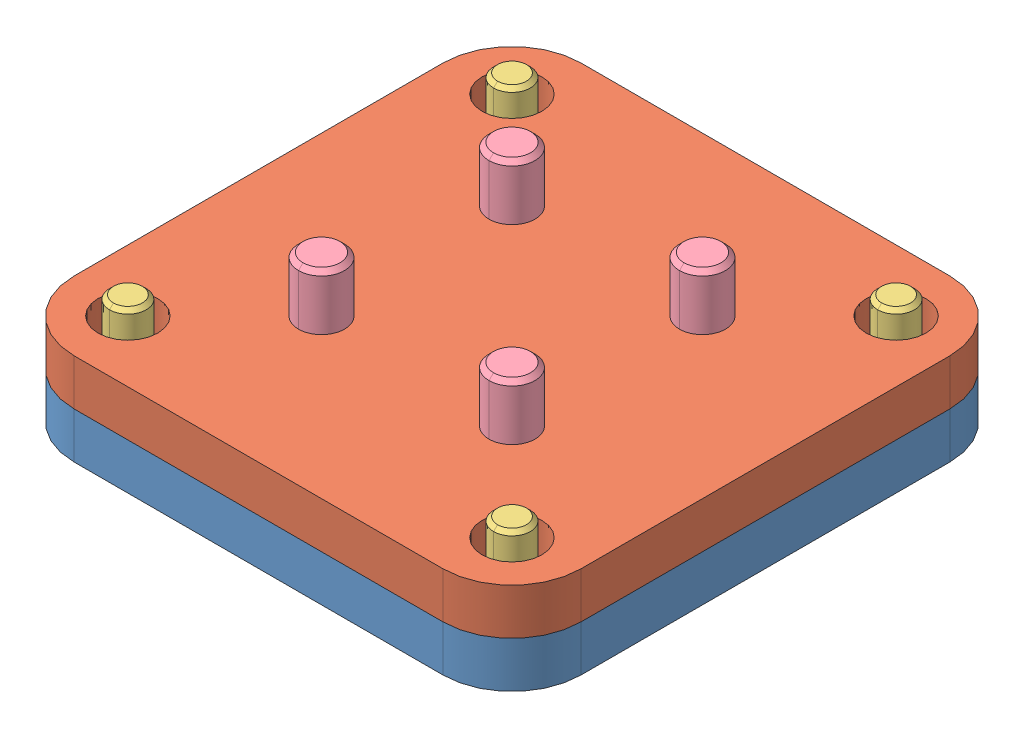
SolidWorks assembly Wheel Adapter V4, configuration Default. Lengths in mm.
Overall size (55.1 18.21 55.1).
10 component instances, 4 part files, 19 mates.
Components (placement in the parent):
- Base plate-1: Base plate [Default] at (35.6102 25.5651 34.2597) size (55.1 5 55.1)
- Connector plate-1: Connector plate [Default] at (35.6102 30.5651 34.2597) size (55.1 5 55.1)
- Screw_ISO_7380_1_M4x12_07151_040_012_High_-2: Screw_ISO_7380_1_M4x12_07151_040_012_High_ [Default] at (14.7402 25.5651 55.1297) x (0 1 0) z (0 0 1) size (14.21 7.6 7.6)
- Screw_ISO_7380_1_M4x12_07151_040_012_High_-3: Screw_ISO_7380_1_M4x12_07151_040_012_High_ [Default] at (14.7402 25.5651 13.3897) x (0 1 0) z (0 0 1) size (14.21 7.6 7.6)
- Screw_ISO_7380_1_M4x12_07151_040_012_High_-4: Screw_ISO_7380_1_M4x12_07151_040_012_High_ [Default] at (56.4802 25.5651 13.3897) x (0 1 0) z (0 0 1) size (14.21 7.6 7.6)
- Screw_ISO_7380_1_M4x12_07151_040_012_High_-5: Screw_ISO_7380_1_M4x12_07151_040_012_High_ [Default] at (56.4802 25.5651 55.1297) x (0 1 0) z (0 0 1) size (14.21 7.6 7.6)
- Screw_ISO_7380_1_M5x8_07150_050_008_High_-1: Screw_ISO_7380_1_M5x8_07150_050_008_High_ [Default] at (45.9602 33.5651 44.6097) x (0 1 0) z (0 0 1) size (10.76 9.5 9.5)
- Screw_ISO_7380_1_M5x8_07150_050_008_High_-2: Screw_ISO_7380_1_M5x8_07150_050_008_High_ [Default] at (45.9602 33.5651 23.9097) x (0 1 0) z (0 0 1) size (10.76 9.5 9.5)
- Screw_ISO_7380_1_M5x8_07150_050_008_High_-3: Screw_ISO_7380_1_M5x8_07150_050_008_High_ [Default] at (25.2602 33.5651 23.9097) x (0 1 0) z (0 0 1) size (10.76 9.5 9.5)
- Screw_ISO_7380_1_M5x8_07150_050_008_High_-4: Screw_ISO_7380_1_M5x8_07150_050_008_High_ [Default] at (25.2602 33.5651 44.6097) x (0 1 0) z (0 0 1) size (10.76 9.5 9.5)
Mates (geometry in assembly coordinates):
- Coincident2: coincident aligned: plane of Base plate-1 through (63.1602 30.5651 61.8097) normal (1 0 0); plane of Connector plate-1 through (63.1602 70.2532 61.8097) normal (1 0 0)
- Coincident3: coincident aligned: plane of Base plate-1 through (8.0602 30.5651 61.8097) normal (0 0 1); plane of Connector plate-1 through (8.0602 70.2532 61.8097) normal (0 0 1)
- Coincident4: coincident anti-aligned: plane of Base plate-1 through (35.6102 25.5651 34.2597) normal (0 -1 0); plane of Screw_ISO_7380_1_M4x12_07151_040_012_High_-2 through (14.7402 25.5651 57.1297) normal (0 1 0)
- Coincident5: coincident aligned: line of Base plate-1 through (14.7402 30.5651 55.1297) axis (0 -1 0); line of Screw_ISO_7380_1_M4x12_07151_040_012_High_-2 through (14.7402 37.1356 55.1297) axis (0 -1 0)
- Coincident6: coincident anti-aligned: plane of Base plate-1 through (35.6102 25.5651 34.2597) normal (0 -1 0); plane of Screw_ISO_7380_1_M4x12_07151_040_012_High_-5 through (56.4802 25.5651 57.1297) normal (0 1 0)
- Coincident7: coincident aligned: line of Base plate-1 through (56.4802 30.5651 55.1297) axis (0 -1 0); line of Screw_ISO_7380_1_M4x12_07151_040_012_High_-5 through (56.4802 37.1356 55.1297) axis (0 -1 0)
- Coincident8: coincident anti-aligned: plane of Base plate-1 through (35.6102 25.5651 34.2597) normal (0 -1 0); plane of Screw_ISO_7380_1_M4x12_07151_040_012_High_-4 through (56.4802 25.5651 15.3897) normal (0 1 0)
- Coincident9: coincident aligned: line of Base plate-1 through (56.4802 30.5651 13.3897) axis (0 -1 0); line of Screw_ISO_7380_1_M4x12_07151_040_012_High_-4 through (56.4802 37.1356 13.3897) axis (0 -1 0)
- Coincident10: coincident anti-aligned: plane of Base plate-1 through (35.6102 25.5651 34.2597) normal (0 -1 0); plane of Screw_ISO_7380_1_M4x12_07151_040_012_High_-3 through (14.7402 25.5651 15.3897) normal (0 1 0)
- Coincident11: coincident aligned: line of Base plate-1 through (14.7402 30.5651 13.3897) axis (0 -1 0); line of Screw_ISO_7380_1_M4x12_07151_040_012_High_-3 through (14.7402 37.1356 13.3897) axis (0 -1 0)
- Coincident12: coincident anti-aligned: plane of Connector plate-1 through (25.2602 68.2532 44.6097) normal (0 -1 0); plane of Screw_ISO_7380_1_M5x8_07150_050_008_High_-4 through (25.2602 68.2532 47.1097) normal (0 1 0)
- Coincident13: coincident aligned: line of Connector plate-1 through (25.2602 68.2532 44.6097) axis (0 -1 0); line of Screw_ISO_7380_1_M5x8_07150_050_008_High_-4 through (25.2602 75.7627 44.6097) axis (0 -1 0)
- Coincident14: coincident anti-aligned: plane of Connector plate-1 through (45.9602 68.2532 44.6097) normal (0 -1 0); plane of Screw_ISO_7380_1_M5x8_07150_050_008_High_-1 through (45.9602 68.2532 47.1097) normal (0 1 0)
- Coincident15: coincident aligned: line of Connector plate-1 through (45.9602 68.2532 44.6097) axis (0 -1 0); line of Screw_ISO_7380_1_M5x8_07150_050_008_High_-1 through (45.9602 75.7627 44.6097) axis (0 -1 0)
- Coincident16: coincident anti-aligned: plane of Connector plate-1 through (45.9602 68.2532 23.9097) normal (0 -1 0); plane of Screw_ISO_7380_1_M5x8_07150_050_008_High_-2 through (45.9602 68.2532 26.4097) normal (0 1 0)
- Coincident17: coincident aligned: line of Connector plate-1 through (45.9602 68.2532 23.9097) axis (0 -1 0); line of Screw_ISO_7380_1_M5x8_07150_050_008_High_-2 through (45.9602 75.7627 23.9097) axis (0 -1 0)
- Coincident18: coincident anti-aligned: plane of Connector plate-1 through (25.2602 68.2532 23.9097) normal (0 -1 0); plane of Screw_ISO_7380_1_M5x8_07150_050_008_High_-3 through (25.2602 68.2532 26.4097) normal (0 1 0)
- Coincident19: coincident aligned: line of Connector plate-1 through (25.2602 68.2532 23.9097) axis (0 -1 0); line of Screw_ISO_7380_1_M5x8_07150_050_008_High_-3 through (25.2602 75.7627 23.9097) axis (0 -1 0)
- Coincident22: coincident anti-aligned: plane of Base plate-1 through (35.6102 30.5651 34.2597) normal (0 1 0); plane of Connector plate-1 through (35.6102 30.5651 34.2597) normal (0 -1 0)
